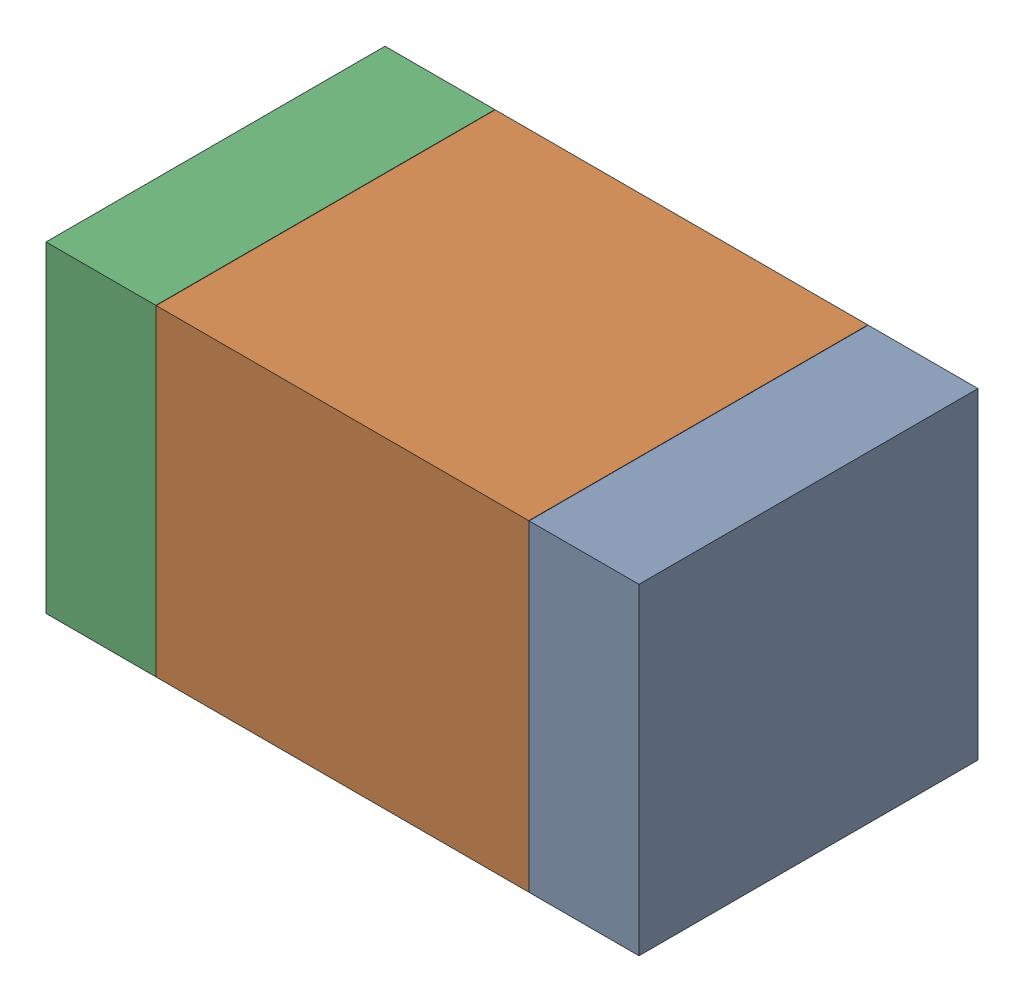
SolidWorks assembly R14, configuration Default. Lengths in mm.
Overall size (1.75 0.95 1).
6 component instances, 2 part files, 0 mates.
Components (placement in the parent):
- 6575498272-1: 6575498272 [Default] at (16.7285 22.479 0) size (0.32 0.95 1)
  - Extruded_8-1: Extruded_8 [Default] at origin size (0.32 0.95 1)
- 6575498112-1: 6575498112 [Default] at (16.016 22.479 0) size (1.1 0.95 1)
  - Extruded_9-1: Extruded_9 [Default] at origin size (1.1 0.95 1)
- 6575498272-2: 6575498272 [Default] at (15.3035 22.479 0) size (0.32 0.95 1)
  - Extruded_8-1: Extruded_8 [Default] at origin size (0.32 0.95 1)
